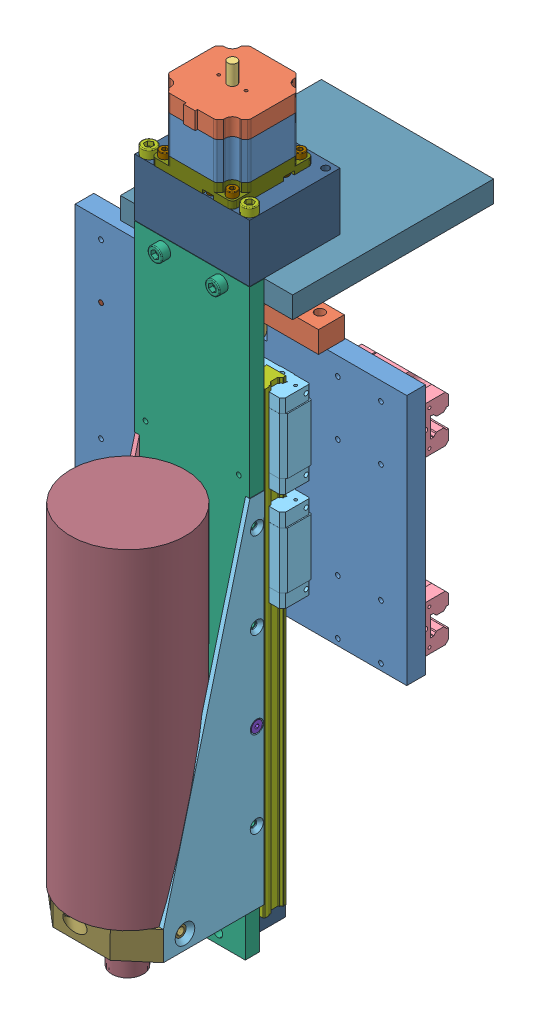
SolidWorks assembly Z_Neu, configuration Standard. Lengths in mm.
Overall size (231 510.29 251.41).
51 component instances, 29 part files, 89 mates.
Components (placement in the parent):
- X-Platte-1: X-Platte [Standard] at (-106.772 84.1214 -5) size (231 175 13)
- mutteraufnahme-1: mutteraufnahme [Standard] at (24.7716 84.1214 -117) x (1 0 0) z (0 1 0) size (120 35.2 15)
- Spindelmutter-1: Spindelmutter [Standard] at (26.8664 109.1214 31.9352) x (-1 0 0) z (0 -1 0) size (54 36.1 40)
- wagen1651-1: wagen1651 [Standard] at (-73.772 52.6214 -29) x (0 1 0) z (1 0 0) size (47 19.9 58.2)
- wagen1622-1: wagen1622 [Standard] at (41.228 29.1214 32) x (1 0 0) z (0 1 0) size (34 19.9 58.2)
- wagen1622-2: wagen1622 [Standard] at (41.228 -39.8786 32) x (1 0 0) z (0 1 0) size (34 19.9 58.2)
- wagen1622-3: wagen1622 [Standard] at (-23.772 29.1214 32) x (-1 0 0) z (0 -1 0) size (34 19.9 58.2)
- wagen1622-4: wagen1622 [Standard] at (-23.772 -39.8786 32) x (-1 0 0) z (0 -1 0) size (34 19.9 58.2)
- test_Z-1: test_Z [Standard] at (39.7107 -85.7173 36.8605) x (0 1 0) z (0 0 1) size (407.5 80 26.2)
  - Z-Platte-1: Z-Platte [Standard] at (-193.0067 67.9827 -4.8605) size (407.5 80 10.28)
  - schiene_15x319-1: schiene_15x319 [Standard] at (-171.5067 63.4827 -4.8605) x (0 1 0) z (-1 0 0) size (15 16.2 319)
  - schiene_15x319-2: schiene_15x319 [Standard] at (-171.5067 -1.5173 -4.8605) x (0 1 0) z (-1 0 0) size (15 16.2 319)
- spindel-1: spindel [Standard] at (8.728 114.0698 14) x (-0.146654 0 -0.989188) z (0 -1 0) size (16 16 420.5)
- wagen1651-2: wagen1651 [Standard] at (-73.772 -67.3786 -29) x (0 -1 0) z (-1 0 0) size (47 19.9 58.2)
- wagen1651-3: wagen1651 [Standard] at (91.228 -67.3786 -29) x (0 -1 0) z (-1 0 0) size (47 19.9 58.2)
- wagen1651-4: wagen1651 [Standard] at (91.228 52.6214 -29) x (0 1 0) z (1 0 0) size (47 19.9 58.2)
- kugellager-1: kugellager [Standard] at (8.728 119.0698 14) x (1 0 0) z (0 -1 0) size (16 16 5)
- Spindellager-2: Spindellager [Standard] at (-16.272 -278.724 2) x (1 0 0) z (0 1 0) size (50 30 15)
- DIN 7984 - M4 x 18 --- 18S-1: DIN 7984 - M4 x 18 --- 18S [DIN 7984 - M4 x 18 --- 18S] at (-88.772 33.6214 -12.8) x (0 0 1) z (0.005003 0.999987 0) size (20.8 7 7)
- kugellager-2: kugellager [Standard] at (8.728 124.0698 14) x (1 0 0) z (0 1 0) size (16 16 5)
- Eurohals-1: Eurohals [Standard] at (-28.2819 -248.7151 42) x (1 -0.000989 0) z (0.000989 1 0) size (80 77.06 20)
- Kress-1: Kress [Standard] at (8.7379 -228.7517 87) x (-0.652176 0.000645 0.758067) z (0.000989 1 0) size (80 80 279)
- Festlager_oben-2: Festlager_oben [Standard] at (-51.272 114.0698 -108) x (1 0 0) z (0 1 0) size (120 140 15)
- kupplung-1: kupplung [Standard] at (8.728 165.0698 14) x (-0.821402 0 0.57035) z (0 -1 0) size (20 20 30)
- kugellager-3: kugellager [Standard] at (8.728 -268.4302 14) x (0.220279 0 -0.975437) z (0 1 0) size (16 16 5)
- nema23-1: nema23 [Standard] at (8.728 173.7698 14) x (1 0 0) z (0 -1 0) size (56.4 58.22 83.1)
  - Frontcap_ST5918_1-1: Frontcap_ST5918_1 [Standard] at (0 0 -6.3) size (56.4 56.4 12.6)
  - shaft_forward_5709_1-1: shaft_forward_5709_1 [Standard] at (0 0 25.3) x (1 0 0) z (0 0 -1) size (6.35 6.35 19)
  - Schrauben_ISO_7045_M3_1-1: Schrauben_ISO_7045_M3_1 [Standard] at (-11.2 -25.35 2.2) x (1 0 0) z (0 -1 0) size (5.57 2.46 5.76)
  - Schrauben_ISO_7045_M3_1-2: Schrauben_ISO_7045_M3_1 [Standard] at (25.35 -11.2 2.2) x (1 0 0) z (0 -1 0) size (5.57 2.46 5.76)
  - Schrauben_ISO_7045_M3_1-3: Schrauben_ISO_7045_M3_1 [Standard] at (11.2 25.35 2.2) x (1 0 0) z (0 -1 0) size (5.57 2.46 5.76)
  - Schrauben_ISO_7045_M3_1-4: Schrauben_ISO_7045_M3_1 [Standard] at (-25.35 11.2 2.2) x (1 0 0) z (0 -1 0) size (5.57 2.46 5.76)
  - Stator_5918_S-1: Stator_5918_S [Standard] at (0 0 -6.3) x (1 0 0) z (0 0 -1) size (56.4 56.4 26)
  - Endcap ST5918_kompl_1-1: Endcap ST5918_kompl_1 [Standard] at (0 0.85 -38.3) x (1 0 0) z (0 0 -1) size (56.4 58.1 12)
    - Endcap_5918_1-1: Endcap_5918_1 [Standard] at (0 0.85 -6) size (56.4 58.1 12)
    - leads_4_ST5918_1-1: leads_4_ST5918_1 [Standard] at (0 -44.05 0.5) x (1 0 0) z (0 1 0)
  - shaft_rear_6.35x13.5_1-1: shaft_rear_6.35x13.5_1 [Standard] at (0 0 -44.3) x (1 0 0) z (0 0 -1) size (6.35 6.35 13.5)
- schräge_li-1: schräge_li [Standard] at (-31.2819 -248.7121 32) x (0.000989 1 0) z (1 -0.000989 0) size (250 70 3)
- schräge_re-1: schräge_re [Standard] at (45.7181 -248.7882 32) x (0.000989 1 0) z (1 -0.000989 0) size (250 70 3)
- DIN  M6 x 30 --- 30C-2: DIN  M6 x 30 --- 30C [DIN  M6 x 30 --- 30C] at (-26.272 108.0698 -16) x (0 1 0) z (-0.998206 0 -0.059875) size (36 10 10)
- DIN  M6 x 30 --- 30C-3: DIN  M6 x 30 --- 30C [DIN  M6 x 30 --- 30C] at (43.728 108.0698 -16) x (0 1 0) z (-1 0 0) size (36 10 10)
- DIN 912 M6 x 60 --- 60C-2: DIN 912 M6 x 60 --- 60C [DIN 912 M6 x 60 --- 60C] at (-26.272 175.0698 37) x (0 -1 0) z (0.511064 0 -0.859543) size (66 10 10)
- DIN 912 M6 x 60 --- 60C-3: DIN 912 M6 x 60 --- 60C [DIN 912 M6 x 60 --- 60C] at (43.728 175.0698 37) x (0 -1 0) z (0.794036 0 0.607871) size (66 10 10)
- DIN  M6 x 30 --- 30C-4: DIN  M6 x 30 --- 30C [DIN  M6 x 30 --- 30C] at (28.728 121.276 48) x (0 0 -1) z (1 0 0) size (36 10 10)
- DIN  M6 x 30 --- 30C-5: DIN  M6 x 30 --- 30C [DIN  M6 x 30 --- 30C] at (-11.272 121.276 48) x (0 0 -1) z (1 0 0) size (36 10 10)
- DIN  M4 x 16 senk-4: DIN  M4 x 16 senk [DIN  M4 x 16 senk] at (48.8282 -138.724 37) x (-1 0 0) z (0 -1 0) size (16 7.64 7.64)
- DIN M4 x 20 --- 20C-7: DIN M4 x 20 --- 20C [DIN M4 x 20 --- 20C] at (-14.842 178.0698 37.57) x (0 -1 0) z (0 0 1) size (24 7 7)
- DIN M4 x 20 --- 20C-8: DIN M4 x 20 --- 20C [DIN M4 x 20 --- 20C] at (32.298 178.0698 37.57) x (0 -1 0) z (0 0 1) size (24 7 7)
- DIN M4 x 20 --- 20C-9: DIN M4 x 20 --- 20C [DIN M4 x 20 --- 20C] at (32.298 178.0698 -9.57) x (0 -1 0) z (0.999937 0 -0.011199) size (24 7 7)
- DIN M4 x 20 --- 20C-10: DIN M4 x 20 --- 20C [DIN M4 x 20 --- 20C] at (-14.842 178.0698 -9.57) x (0 -1 0) z (0.687024 0 0.726634) size (24 7 7)
- motoradapter-2: motoradapter [Standard] at (48.728 169.0698 -21) x (-1 0 0) z (0 -1 0) size (80 63 40)
Mates (geometry in assembly coordinates):
- Deckungsgleich1: coincident anti-aligned: plane of X-Platte-1 through (8.728 84.1214 8) normal (0 1 0); plane of mutteraufnahme-1 through (68.728 84.1214 33) normal (0 -1 0)
- Deckungsgleich2: coincident anti-aligned: plane of mutteraufnahme-1 through (68.728 99.1214 33) normal (0 1 0); plane of Spindelmutter-1 through (8.728 99.1214 11.9352) normal (0 -1 0)
- Konzentrisch3: concentric aligned: cylinder of mutteraufnahme-1 through (8.728 84.1214 14) axis (0 1 0) radius 17; cylinder of Spindelmutter-1 through (8.728 69.1214 14) axis (0 1 0) radius 17
- Deckungsgleich3: coincident anti-aligned: plane of wagen1651-1 through (-54.172 76.1214 -5) normal (0 0 1); plane of X-Platte-1 through (8.728 -228.9342 -5) normal (0 0 -1)
- Konzentrisch8: concentric anti-aligned: cylinder of X-Platte-1 through (-88.772 71.6214 8) axis (0 0 1) radius 1.65; cylinder of wagen1651-1 through (-88.772 71.6214 -10) axis (0 0 -1) radius 2.2
- Konzentrisch9: concentric anti-aligned: cylinder of X-Platte-1 through (-58.772 71.6214 8) axis (0 0 1) radius 1.65; cylinder of wagen1651-1 through (-58.772 71.6214 -10) axis (0 0 -1) radius 2.2
- Deckungsgleich5: coincident anti-aligned: plane of X-Platte-1 through (8.728 -228.9342 8) normal (0 0 1); plane of wagen1622-3 through (-40.772 9.5214 8) normal (0 0 -1)
- Deckungsgleich7: coincident anti-aligned: plane of X-Platte-1 through (8.728 -228.9342 8) normal (0 0 1); plane of wagen1622-4 through (-40.772 -59.4786 8) normal (0 0 -1)
- Deckungsgleich8: coincident anti-aligned: plane of X-Platte-1 through (8.728 -228.9342 8) normal (0 0 1); plane of wagen1622-1 through (58.228 48.7214 8) normal (0 0 -1)
- Deckungsgleich10: coincident anti-aligned: plane of X-Platte-1 through (8.728 -228.9342 8) normal (0 0 1); plane of wagen1622-2 through (58.228 -20.2786 8) normal (0 0 -1)
- Konzentrisch10: concentric anti-aligned: cylinder of X-Platte-1 through (28.228 42.1214 8) axis (0 0 1) radius 2.25; cylinder of wagen1622-1 through (28.228 42.1214 8) axis (0 0 -1) radius 1.6
- Konzentrisch11: concentric anti-aligned: cylinder of X-Platte-1 through (28.228 16.1214 8) axis (0 0 1) radius 2.25; cylinder of wagen1622-1 through (28.228 16.1214 8) axis (0 0 -1) radius 1.6
- Konzentrisch12: concentric anti-aligned: cylinder of X-Platte-1 through (28.228 -52.8786 8) axis (0 0 1) radius 2.25; cylinder of wagen1622-2 through (28.228 -52.8786 8) axis (0 0 -1) radius 1.6
- Konzentrisch13: concentric anti-aligned: cylinder of X-Platte-1 through (28.228 -26.8786 8) axis (0 0 1) radius 2.25; cylinder of wagen1622-2 through (28.228 -26.8786 8) axis (0 0 -1) radius 1.6
- Konzentrisch15: concentric anti-aligned: cylinder of X-Platte-1 through (-10.772 -52.8786 8) axis (0 0 1) radius 2.25; cylinder of wagen1622-4 through (-10.772 -52.8786 8) axis (0 0 -1) radius 1.6
- Konzentrisch16: concentric anti-aligned: cylinder of X-Platte-1 through (-10.772 -26.8786 8) axis (0 0 1) radius 2.25; cylinder of wagen1622-4 through (-10.772 -26.8786 8) axis (0 0 -1) radius 1.6
- Konzentrisch17: concentric anti-aligned: cylinder of X-Platte-1 through (-10.772 16.1214 8) axis (0 0 1) radius 2.25; cylinder of wagen1622-3 through (-10.772 16.1214 8) axis (0 0 -1) radius 1.6
- Konzentrisch18: concentric anti-aligned: cylinder of X-Platte-1 through (-10.772 42.1214 8) axis (0 0 1) radius 2.25; cylinder of wagen1622-3 through (-10.772 42.1214 8) axis (0 0 -1) radius 1.6
- Konzentrisch23: concentric aligned: cylinder of wagen1622-3 through (-30.818 58.2214 19.546) axis (0 -1 0) radius 1.65; cylinder of test_Z-1/schiene_15x319-1 through (-30.818 -257.224 19.546) axis (0 -1 0) radius 1.65
- Konzentrisch24: concentric anti-aligned: cylinder of wagen1622-1 through (48.274 0.0214 19.546) axis (0 1 0) radius 1.65; cylinder of test_Z-1/schiene_15x319-2 through (48.274 -257.224 19.546) axis (0 -1 0) radius 1.65
- Konzentrisch25: concentric aligned: cylinder of Spindelmutter-1 through (8.728 69.1214 14) axis (0 -1 0) radius 7; cylinder of spindel-1 through (8.728 135.0698 14) axis (0 -1 0) radius 4
- Deckungsgleich16: coincident anti-aligned: plane of X-Platte-1 through (8.728 -228.9342 -5) normal (0 0 -1); plane of wagen1651-4 through (110.828 76.1214 -5) normal (0 0 1)
- Deckungsgleich17: coincident anti-aligned: plane of X-Platte-1 through (8.728 -228.9342 -5) normal (0 0 -1); plane of wagen1651-2 through (-93.372 -90.8786 -5) normal (0 0 1)
- Deckungsgleich18: coincident anti-aligned: plane of X-Platte-1 through (8.728 -228.9342 -5) normal (0 0 -1); plane of wagen1651-3 through (71.628 -90.8786 -5) normal (0 0 1)
- Konzentrisch26: concentric anti-aligned: cylinder of X-Platte-1 through (106.228 71.6214 8) axis (0 0 1) radius 1.65; cylinder of wagen1651-4 through (106.228 71.6214 -10) axis (0 0 -1) radius 2.2
- Konzentrisch27: concentric anti-aligned: cylinder of X-Platte-1 through (76.228 33.6214 8) axis (0 0 1) radius 1.65; cylinder of wagen1651-4 through (76.228 33.6214 -10) axis (0 0 -1) radius 2.2
- Konzentrisch30: concentric anti-aligned: cylinder of X-Platte-1 through (76.228 -48.3786 8) axis (0 0 1) radius 1.65; cylinder of wagen1651-3 through (76.228 -48.3786 -10) axis (0 0 -1) radius 2.2
- Konzentrisch31: concentric anti-aligned: cylinder of X-Platte-1 through (76.228 -86.3786 8) axis (0 0 1) radius 1.65; cylinder of wagen1651-3 through (76.228 -86.3786 -10) axis (0 0 -1) radius 2.2
- Konzentrisch32: concentric anti-aligned: cylinder of X-Platte-1 through (-88.772 -48.3786 8) axis (0 0 1) radius 1.65; cylinder of wagen1651-2 through (-88.772 -48.3786 -10) axis (0 0 -1) radius 2.2
- Konzentrisch33: concentric anti-aligned: cylinder of X-Platte-1 through (-58.772 -86.3786 8) axis (0 0 1) radius 1.65; cylinder of wagen1651-2 through (-58.772 -86.3786 -10) axis (0 0 -1) radius 2.2
- Parallel4: parallel anti-aligned: plane of Spindelmutter-1 through (27.8118 109.1214 31.0352) normal (0 0 1); plane of test_Z-1/Z-Platte-1 through (-28.272 -278.724 32) normal (0 0 -1)
- Deckungsgleich28: coincident anti-aligned: plane of spindel-1 through (8.728 114.0698 14) normal (0 1 0); plane of kugellager-1 through (8.728 114.0698 14) normal (0 -1 0)
- Deckungsgleich29: coincident anti-aligned: plane of test_Z-1/Z-Platte-1 through (-28.272 -278.724 32) normal (0 0 -1); plane of Spindellager-2 through (-16.272 -263.724 32) normal (0 0 1)
- Konzentrisch38: concentric aligned: cylinder of test_Z-1/Z-Platte-1 through (-9.272 -271.224 42) axis (0 0 1) radius 3.3; cylinder of Spindellager-2 through (-9.272 -271.224 32) axis (0 0 1) radius 2.5
- Konzentrisch39: concentric aligned: cylinder of test_Z-1/Z-Platte-1 through (26.728 -271.224 42) axis (0 0 1) radius 3.3; cylinder of Spindellager-2 through (26.728 -271.224 32) axis (0 0 1) radius 2.5
- Konzentrisch40: concentric aligned: cylinder of wagen1651-1 through (-88.772 33.6214 -10) axis (0 0 -1) radius 2.2; cylinder of DIN 7984 - M4 x 18 --- 18S-1 through (-88.772 33.6214 -44.55) axis (0 0 -1) radius 3.5
- Deckungsgleich31: coincident anti-aligned: plane of wagen1651-1 through (-93.372 36.4214 -10) normal (0 0 -1); plane of DIN 7984 - M4 x 18 --- 18S-1 through (-85.272 33.6039 -10) normal (0 0 1)
- Deckungsgleich32: coincident aligned: plane of X-Platte-1 through (8.728 -228.9342 8) normal (0 0 1); plane of DIN 7984 - M4 x 18 --- 18S-1 through (-87.162 33.6133 8) normal (0 0 1)
- Parallel6: parallel aligned: plane of mutteraufnahme-1 through (-51.272 99.1214 -4) normal (0 0 -1); plane of Spindelmutter-1 through (-12.2481 99.1214 -5.0648) normal (0 0 -1)
- Konzentrisch45: concentric aligned: cylinder of X-Platte-1 through (58.728 84.1214 3) axis (0 1 0) radius 2.5; cylinder of mutteraufnahme-1 through (58.728 99.1214 3) axis (0 1 0) radius 3.3
- Deckungsgleich40: coincident anti-aligned: plane of test_Z-1/Z-Platte-1 through (-28.272 -278.724 42) normal (0 0 1); plane of Eurohals-1 through (-28.2621 -228.7151 42) normal (0 0 -1)
- Konzentrisch47: concentric aligned: cylinder of test_Z-1/Z-Platte-1 through (21.728 -238.724 32) axis (0 0 -1) radius 3.2; cylinder of Eurohals-1 through (21.728 -238.724 42) axis (0 0 -1) radius 3
- Konzentrisch48: concentric aligned: cylinder of test_Z-1/Z-Platte-1 through (-19.272 -238.724 32) axis (0 0 -1) radius 4.5; cylinder of Eurohals-1 through (-19.272 -238.724 42) axis (0 0 -1) radius 3.4
- Konzentrisch49: concentric aligned: cylinder of Eurohals-1 through (8.7379 -228.7517 87) axis (0.000989 1 0) radius 21.5; cylinder of Kress-1 through (8.7142 -252.7516 87) axis (0.000989 1 0) radius 21.5
- Deckungsgleich43: coincident anti-aligned: plane of Eurohals-1 through (-28.2621 -228.7151 102) normal (0.000989 1 0); plane of Kress-1 through (8.7379 -228.7517 87) normal (-0.000989 -1 0)
- Konzentrisch50: concentric anti-aligned: cylinder of spindel-1 through (8.728 135.0698 14) axis (0 -1 0) radius 4; cylinder of kugellager-1 through (8.728 114.0698 14) axis (0 1 0) radius 4
- Deckungsgleich46: coincident anti-aligned: plane of kugellager-1 through (8.728 119.0698 14) normal (0 1 0); plane of Festlager_oben-2 through (8.728 119.0698 14) normal (0 -1 0)
- Deckungsgleich47: coincident anti-aligned: plane of kugellager-2 through (8.728 124.0698 14) normal (0 -1 0); plane of Festlager_oben-2 through (8.728 124.0698 14) normal (0 1 0)
- Konzentrisch56: concentric aligned: cylinder of spindel-1 through (8.728 147.0698 14) axis (0 -1 0) radius 2.5; cylinder of kupplung-1 through (8.728 145.0698 14) axis (0 -1 0) radius 2.5
- Deckungsgleich48: coincident anti-aligned: plane of spindel-1 through (8.728 135.0698 14) normal (0 1 0); plane of kupplung-1 through (8.728 135.0698 14) normal (0 -1 0)
- Deckungsgleich52: coincident anti-aligned: plane of test_Z-1/Z-Platte-1 through (-28.272 -278.724 32) normal (0 0 -1); plane of Festlager_oben-2 through (-51.272 129.0698 32) normal (0 0 1)
- Konzentrisch64: concentric anti-aligned: cylinder of spindel-1 through (8.728 -273.4302 14) axis (0 1 0) radius 4; cylinder of kugellager-3 through (8.728 -263.4302 14) axis (0 -1 0) radius 4
- Deckungsgleich53: coincident anti-aligned: plane of spindel-1 through (8.728 -263.4302 14) normal (0 -1 0); plane of kugellager-3 through (8.728 -263.4302 14) normal (0 1 0)
- Konzentrisch68: concentric aligned: cylinder of kupplung-1 through (8.728 155.0698 14) axis (0 1 0) radius 3.175; cylinder of nema23-1/shaft_forward_5709_1-1 through (8.728 148.4698 14) axis (0 1 0) radius 3.175
- Deckungsgleich71: coincident aligned: plane of Eurohals-1 through (-28.2819 -248.7151 102) normal (-0.000989 -1 0); plane of schräge_li-1 through (-28.2819 -248.7151 102) normal (-0.000989 -1 0)
- Deckungsgleich72: coincident aligned: plane of test_Z-1/Z-Platte-1 through (-28.272 -278.724 32) normal (0 0 -1); plane of schräge_li-1 through (-28.2819 -248.7151 32) normal (0 0 -1)
- Deckungsgleich73: coincident anti-aligned: plane of Eurohals-1 through (-28.2621 -228.7151 42) normal (-1 0.000989 0); plane of schräge_li-1 through (-28.2819 -248.7151 32) normal (1 -0.000989 0)
- Deckungsgleich86: coincident aligned: plane of Eurohals-1 through (-28.2819 -248.7151 102) normal (-0.000989 -1 0); plane of schräge_re-1 through (48.7181 -248.7912 102) normal (-0.000989 -1 0)
- Deckungsgleich90: coincident anti-aligned: plane of Eurohals-1 through (45.7379 -228.7883 42) normal (1 -0.000989 0); plane of schräge_re-1 through (45.7181 -248.7882 32) normal (-1 0.000989 0)
- Deckungsgleich93: coincident aligned: plane of test_Z-1/Z-Platte-1 through (-28.272 -278.724 32) normal (0 0 -1); plane of schräge_re-1 through (48.7181 -248.7912 32) normal (0 0 -1)
- Konzentrisch83: concentric anti-aligned: cylinder of Festlager_oben-2 through (-26.272 129.0698 -16) axis (0 1 0) radius 3.3; cylinder of DIN  M6 x 30 --- 30C-2 through (-26.272 76.3198 -16) axis (0 -1 0) radius 3
- Deckungsgleich104: coincident anti-aligned: plane of Festlager_oben-2 through (-51.272 114.0698 32) normal (0 -1 0); plane of DIN  M6 x 30 --- 30C-2 through (-25.9726 114.0698 -20.991) normal (0 1 0)
- Konzentrisch84: concentric anti-aligned: cylinder of Festlager_oben-2 through (43.728 129.0698 -16) axis (0 1 0) radius 3.3; cylinder of DIN  M6 x 30 --- 30C-3 through (43.728 76.3198 -16) axis (0 -1 0) radius 3
- Deckungsgleich105: coincident anti-aligned: plane of Festlager_oben-2 through (-51.272 114.0698 32) normal (0 -1 0); plane of DIN  M6 x 30 --- 30C-3 through (43.728 114.0698 -21) normal (0 1 0)
- Konzentrisch85: concentric aligned: cylinder of test_Z-1/Z-Platte-1 through (28.728 121.276 42) axis (0 0 1) radius 3; cylinder of DIN  M6 x 30 --- 30C-4 through (28.728 121.276 79.75) axis (0 0 1) radius 3
- Deckungsgleich106: coincident anti-aligned: plane of test_Z-1/Z-Platte-1 through (-28.272 -278.724 42) normal (0 0 1); plane of DIN  M6 x 30 --- 30C-4 through (28.728 126.276 42) normal (0 0 -1)
- Konzentrisch86: concentric aligned: cylinder of test_Z-1/Z-Platte-1 through (-11.272 121.276 42) axis (0 0 1) radius 3; cylinder of DIN  M6 x 30 --- 30C-5 through (-11.272 121.276 79.75) axis (0 0 1) radius 3
- Deckungsgleich107: coincident anti-aligned: plane of test_Z-1/Z-Platte-1 through (-28.272 -278.724 42) normal (0 0 1); plane of DIN  M6 x 30 --- 30C-5 through (-11.272 126.276 42) normal (0 0 -1)
- Konzentrisch88: concentric aligned: cylinder of test_Z-1/Z-Platte-1 through (45.728 -138.724 37) axis (1 0 0) radius 1.65; cylinder of DIN  M4 x 16 senk-4 through (48.8282 -138.724 37) axis (1 0 0) radius 2
- Deckungsgleich108: coincident: plane of schräge_re-1 through (48.7181 -248.7912 32) normal (1 -0.000989 0); line of DIN  M4 x 16 senk-4 through (48.8282 -137.464 37.7275) axis (0 0 -1)
- Konzentrisch97: concentric anti-aligned: cylinder of nema23-1/Frontcap_ST5918_1-1 through (-14.842 169.0698 37.57) axis (0 1 0) radius 2.5; circle of DIN M4 x 20 --- 20C-7
- Deckungsgleich113: coincident anti-aligned: plane of nema23-1/Frontcap_ST5918_1-1 through (-14.7348 174.0698 37.4628) normal (0 1 0); plane of DIN M4 x 20 --- 20C-7 through (-11.342 174.0698 37.57) normal (0 -1 0)
- Konzentrisch98: concentric aligned: cylinder of nema23-1/Frontcap_ST5918_1-1 through (32.298 169.0698 37.57) axis (0 1 0) radius 2.5; cylinder of DIN M4 x 20 --- 20C-8 through (32.298 209.8198 37.57) axis (0 1 0) radius 2
- Deckungsgleich114: coincident anti-aligned: plane of nema23-1/Frontcap_ST5918_1-1 through (32.1909 174.0698 37.4628) normal (0 1 0); plane of DIN M4 x 20 --- 20C-8 through (35.798 174.0698 37.57) normal (0 -1 0)
- Konzentrisch101: concentric aligned: cylinder of nema23-1/Frontcap_ST5918_1-1 through (32.298 169.0698 -9.57) axis (0 1 0) radius 2.5; cylinder of DIN M4 x 20 --- 20C-9 through (32.298 209.8198 -9.57) axis (0 1 0) radius 2
- Deckungsgleich115: coincident anti-aligned: plane of nema23-1/Frontcap_ST5918_1-1 through (32.1909 174.0698 -9.4628) normal (0 1 0); plane of DIN M4 x 20 --- 20C-9 through (32.2588 174.0698 -13.0698) normal (0 -1 0)
- Konzentrisch102: concentric aligned: cylinder of nema23-1/Frontcap_ST5918_1-1 through (-14.842 169.0698 -9.57) axis (0 1 0) radius 2.5; cylinder of DIN M4 x 20 --- 20C-10 through (-14.842 209.8198 -9.57) axis (0 1 0) radius 3.5
- Deckungsgleich118: coincident anti-aligned: plane of nema23-1/Frontcap_ST5918_1-1 through (-14.7348 174.0698 -9.4628) normal (0 1 0); plane of DIN M4 x 20 --- 20C-10 through (-12.2987 174.0698 -11.9746) normal (0 -1 0)
- Konzentrisch103: concentric aligned: cylinder of Festlager_oben-2 through (-11.272 121.276 32) axis (0 0 1) radius 2.5; cylinder of DIN  M6 x 30 --- 30C-5 through (-11.272 121.276 79.75) axis (0 0 1) radius 3
- Deckungsgleich119: coincident anti-aligned: plane of Festlager_oben-2 through (-51.272 129.0698 32) normal (0 1 0); plane of motoradapter-2 through (48.728 129.0698 49) normal (0 -1 0)
- Konzentrisch107: concentric aligned: cylinder of test_Z-1/Z-Platte-1 through (-26.272 128.776 37) axis (0 1 0) radius 2.5; cylinder of motoradapter-2 through (-26.272 169.0698 37) axis (0 1 0) radius 3.3
- Konzentrisch108: concentric aligned: cylinder of test_Z-1/Z-Platte-1 through (43.728 128.776 37) axis (0 1 0) radius 2.5; cylinder of motoradapter-2 through (43.728 169.0698 37) axis (0 1 0) radius 3.3
- Deckungsgleich123: coincident anti-aligned: plane of nema23-1/Frontcap_ST5918_1-1 through (8.728 169.0698 14) normal (0 -1 0); plane of motoradapter-2 through (48.728 169.0698 49) normal (0 1 0)
- Parallel8: parallel aligned: plane of nema23-1/Frontcap_ST5918_1-1 through (-19.472 180.0698 42.2) normal (0 0 1); plane of motoradapter-2 through (-31.272 129.0698 42) normal (0 0 1)
- Konzentrisch112: concentric aligned: cylinder of DIN 912 M6 x 60 --- 60C-3 through (43.728 206.8198 37) axis (0 1 0) radius 3; cylinder of motoradapter-2 through (43.728 169.0698 37) axis (0 1 0) radius 3.3
- Deckungsgleich126: coincident anti-aligned: plane of DIN 912 M6 x 60 --- 60C-3 through (46.7674 169.0698 33.0298) normal (0 -1 0); plane of motoradapter-2 through (48.728 169.0698 49) normal (0 1 0)
- Konzentrisch113: concentric aligned: cylinder of DIN 912 M6 x 60 --- 60C-2 through (-26.272 206.8198 37) axis (0 1 0) radius 3; cylinder of motoradapter-2 through (-26.272 169.0698 37) axis (0 1 0) radius 3.3
- Deckungsgleich127: coincident anti-aligned: plane of DIN 912 M6 x 60 --- 60C-2 through (-30.5697 169.0698 34.4447) normal (0 -1 0); plane of motoradapter-2 through (48.728 169.0698 49) normal (0 1 0)
- EBENE1: unknown: moEndPointRef_w of test_Z-1/Z-Platte-1; line of test_Z-1/Z-Platte-1 through (45.728 -281.3407 42) axis (0 1 0)
